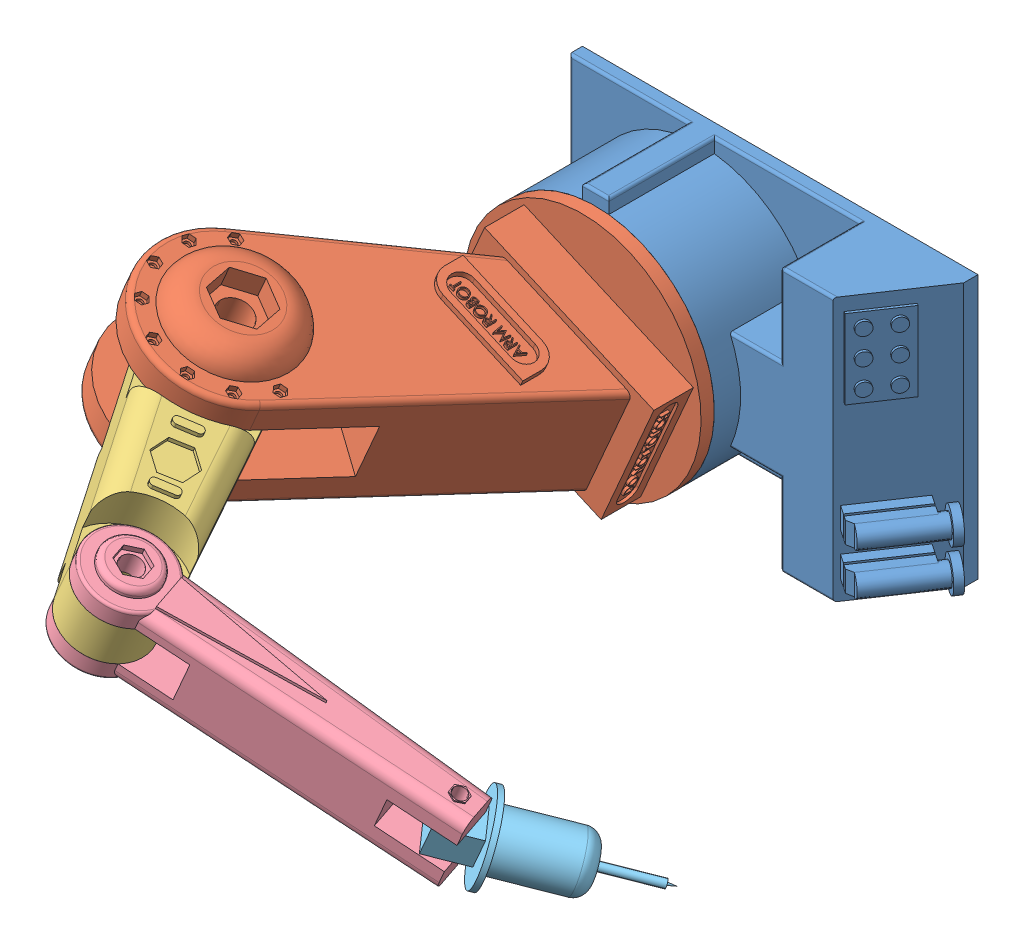
SolidWorks assembly NOP, configuration Default. Lengths in mm.
Overall size (241.62 149.77 246.64).
5 component instances, 5 part files, 8 mates.
Components (placement in the parent):
- de robot-1: de robot [Default] at origin size (160.95 100 55)
- link 1-1: link 1 [Default] at (-45.8413 19.9644 145) x (0.916826 -0.399288 0) z (0.399288 0.916826 0) size (125 130 90)
- link 2-1: link 2 [Default] at (-4.5353 1.9752 222.9115) x (0.441337 -0.192207 0.876515) z (0.399288 0.916826 0) size (124.98 40 48)
- link 3-1: link 3 [Default] at (90.7021 -39.5017 193.3563) x (0.881827 -0.384045 -0.27366) z (0.399288 0.916826 0) size (130 30 36)
- link 4-1: link 4 [Default] at (133.0111 -57.8937 151.1907) x (0.676745 -0.29473 -0.674648) z (0.399288 0.916826 0) size (70 30 30)
Mates (geometry in assembly coordinates):
- Concentric17: concentric aligned: cylinder of de robot-1 through (0 0 55) axis (0 0 -1) radius 10; cylinder of link 1-1 through (0 0 55) axis (0 0 -1) radius 10
- Coincident17: coincident anti-aligned: plane of de robot-1 through (0 0 45) normal (0 0 1); plane of link 1-1 through (0 0 45) normal (0 0 -1)
- Concentric18: concentric aligned: cylinder of link 1-1 through (-46.8395 17.6723 145) axis (-0.399288 -0.916826 0) radius 6; cylinder of link 2-1 through (-34.4616 46.0939 145) axis (-0.399288 -0.916826 0) radius 6
- Coincident18: coincident anti-aligned: plane of link 1-1 through (-68.0969 17.1136 92.0938) normal (0.399288 0.916826 0); plane of link 2-1 through (-50.4331 9.4209 145) normal (-0.399288 -0.916826 0)
- Concentric19: concentric aligned: cylinder of link 2-1 through (6.8444 28.1047 222.9115) axis (-0.399288 -0.916826 0) radius 4; cylinder of link 3-1 through (1.454 15.7276 222.9115) axis (-0.399288 -0.916826 0) radius 4
- Coincident21: coincident anti-aligned: plane of link 2-1 through (-1.341 9.3098 222.9115) normal (0.399288 0.916826 0); plane of link 3-1 through (-1.341 9.3098 222.9115) normal (-0.399288 -0.916826 0)
- Concentric20: concentric anti-aligned: cylinder of link 3-1 through (97.8892 -22.9989 193.3563) axis (-0.399288 -0.916826 0) radius 2.5; cylinder of link 4-1 through (84.7252 -53.2254 193.3563) axis (0.399288 0.916826 0) radius 2.5
- Coincident22: coincident anti-aligned: plane of link 3-1 through (-6.931 -3.5258 222.9115) normal (0.399288 0.916826 0); plane of link 4-1 through (88.9722 -45.2927 200.821) normal (-0.399288 -0.916826 0)
